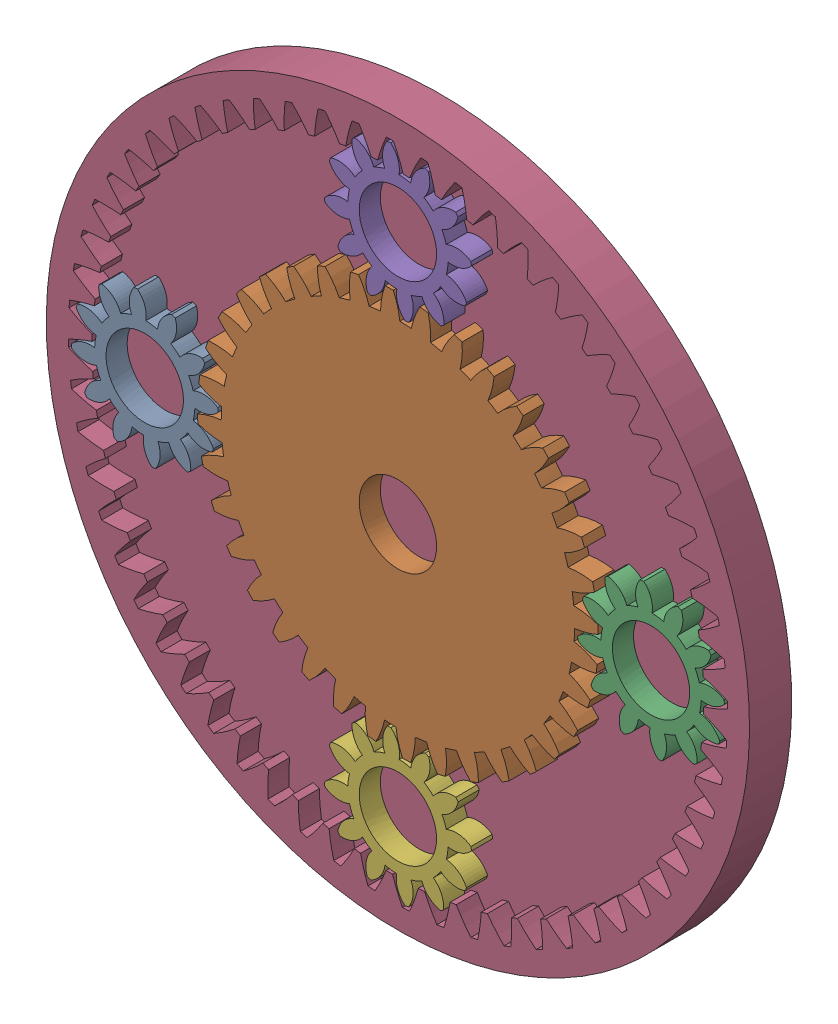
SolidWorks assembly Assem1, configuration Default. Lengths in mm.
Overall size (280.36 280.36 12).
6 component instances, 3 part files, 17 mates.
Components (placement in the parent):
- part1_planet_gear_orbit-2: part1_planet_gear_orbit [Default] at (-99.3044 14.7025 -52.289) x (0 0 -1) z (0.788339 -0.615241 0) size (6 40.83 40.83)
- part2_platet_gear_sun-3: part2_platet_gear_sun [Default] at (3.7977 -10.9258 -13.5271) x (0 0 -1) z (-0.461919 0.886922 0) size (6 113.75 113.75)
- part1_planet_gear_orbit-3: part1_planet_gear_orbit [Default] at (44.6734 14.6611 -52.289) x (0 0 -1) z (0.789269 -0.614048 0) size (6 40.83 40.83)
- part3_planet_outer-2: part3_planet_outer [Metric - Internal spur gear 3M 60T 20PA 12FW ---S60S200OD 1AF] at (0 0 -6) x (0 0 1) z (0.794388 0.607411 0) size (12 200 200)
- part1_planet_gear_orbit-4: part1_planet_gear_orbit [Default] at (-30.9977 71.0858 -52.289) x (0 0 -1) z (0.990318 -0.138815 0) size (6 40.83 40.83)
- part1_planet_gear_orbit-5: part1_planet_gear_orbit [Default] at (0.8057 -103.0007 -52.289) x (0 0 -1) z (0.142279 0.989827 0) size (6 40.83 40.83)
Mates (geometry in assembly coordinates):
- Concentric12: concentric aligned: cylinder of part1_planet_gear_orbit-2 through (-72 0 -44.0001) axis (0 0 1) radius 11
- Coincident5: coincident anti-aligned: plane of part1_planet_gear_orbit-2 through (-72 0 0) normal (0 0 -1)
- Concentric14: concentric aligned: cylinder of part2_platet_gear_sun-3 through (0 0 -44.0001) axis (0 0 1) radius 11
- Coincident8: coincident anti-aligned: plane of part2_platet_gear_sun-3 through (0 0 0) normal (0 0 -1)
- Coincident9: coincident anti-aligned: plane of part1_planet_gear_orbit-3 through (72 0 0) normal (0 0 -1)
- Concentric15: concentric aligned: cylinder of part1_planet_gear_orbit-3 through (72 0 -44.0001) axis (0 0 1) radius 11
- Concentric17: concentric anti-aligned: cylinder of part3_planet_outer-2 through (0 0 -16) axis (0 0 -1) radius 100
- GearMate1: gear = 36 : 12 mm: circle of part1_planet_gear_orbit-3; cylinder of part2_platet_gear_sun-3 through (0 0 -44.0001) axis (0 0 1) radius 11
- GearMate2: gear = 36 : 12 mm: cylinder of part1_planet_gear_orbit-2 through (-72 0 -44.0001) axis (0 0 1) radius 11; cylinder of part2_platet_gear_sun-3 through (0 0 -44.0001) axis (0 0 1) radius 11
- GearMate4: gear = 60 : 12 mm: cylinder of part1_planet_gear_orbit-2 through (-72 0 -44.0001) axis (0 0 1) radius 11; cylinder of part3_planet_outer-2 through (0 0 -16) axis (0 0 -1) radius 100
- Coincident17: coincident aligned: plane of part2_platet_gear_sun-3 through (0 0 6) normal (0 0 1); plane of part3_planet_outer-2 through (-69.1117 -52.8447 6) normal (0 0 1)
- Coincident19: coincident anti-aligned: plane of part3_planet_outer-2 through (0 0 0) normal (0 0 1); plane of part1_planet_gear_orbit-5 through (0 -72 0) normal (0 0 -1)
- Concentric20: concentric aligned: circle of part1_planet_gear_orbit-5
- Concentric21: concentric aligned: cylinder of part1_planet_gear_orbit-4 through (0 72 -44.0001) axis (0 0 1) radius 11
- Coincident20: coincident anti-aligned: plane of part3_planet_outer-2 through (0 0 0) normal (0 0 1); plane of part1_planet_gear_orbit-4 through (0 72 0) normal (0 0 -1)
- GearMate5: gear = 60 : 12 mm: circle of part1_planet_gear_orbit-4; cylinder of part3_planet_outer-2 through (0 0 -16) axis (0 0 -1) radius 100
- GearMate6: gear = 60 : 12 mm: cylinder of part1_planet_gear_orbit-5 through (0 -72 -44.0001) axis (0 0 1) radius 11; cylinder of part3_planet_outer-2 through (0 0 -16) axis (0 0 -1) radius 100
